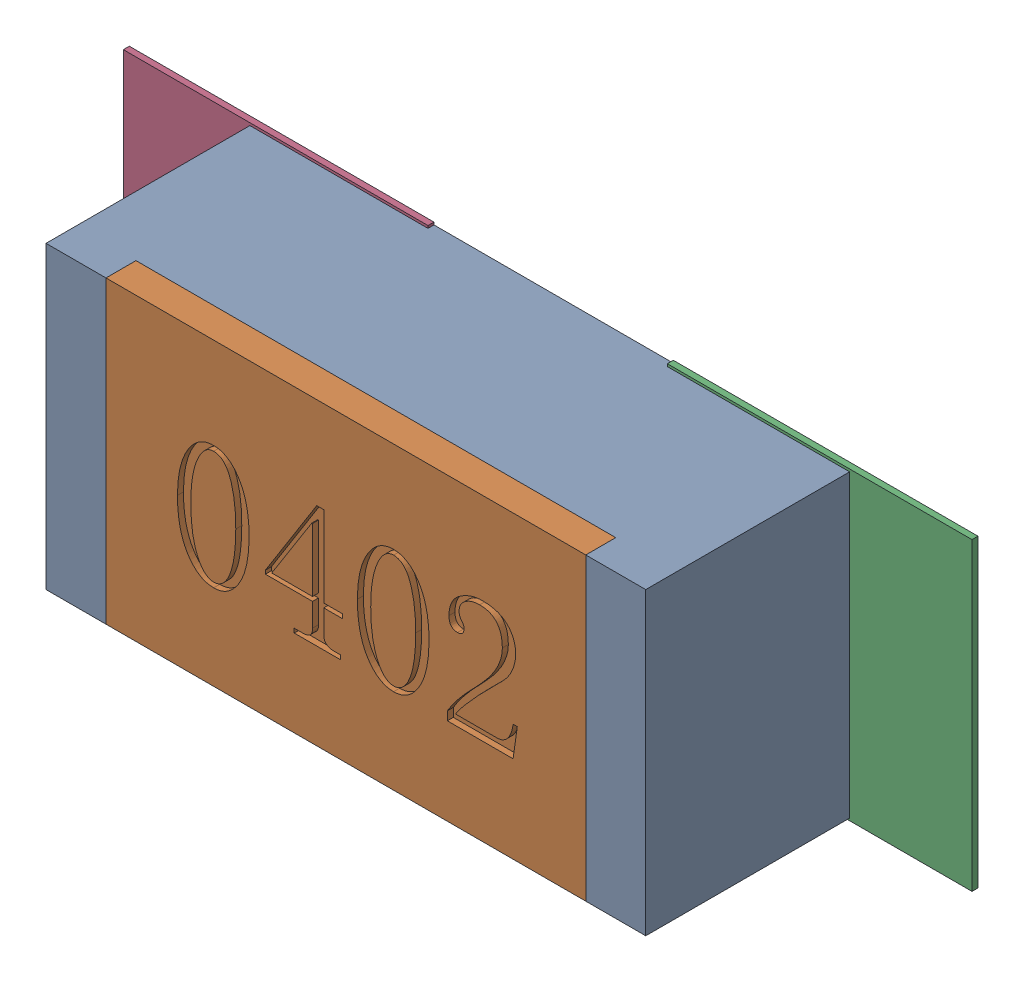
SolidWorks assembly R148, configuration Défaut. Lengths in mm.
Overall size (1.42 0.51 0.35).
5 component instances, 2 part files, 0 mates.
Components (placement in the parent):
- R0402-1: R0402 [Défaut] at (12.1976 -23.7025 0) x (1 0 0) z (0 0 1) size (1 0.5 0.35)
- 6504207776-1: 6504207776 [Défaut] at (12.6476 -23.7024 0) size (0.51 0.51 0.01)
  - Extruded-1: Extruded [Défaut] at origin size (0.51 0.51 0.01)
- 6504207776-2: 6504207776 [Défaut] at (11.7405 -23.7024 0) size (0.51 0.51 0.01)
  - Extruded-1: Extruded [Défaut] at origin size (0.51 0.51 0.01)
